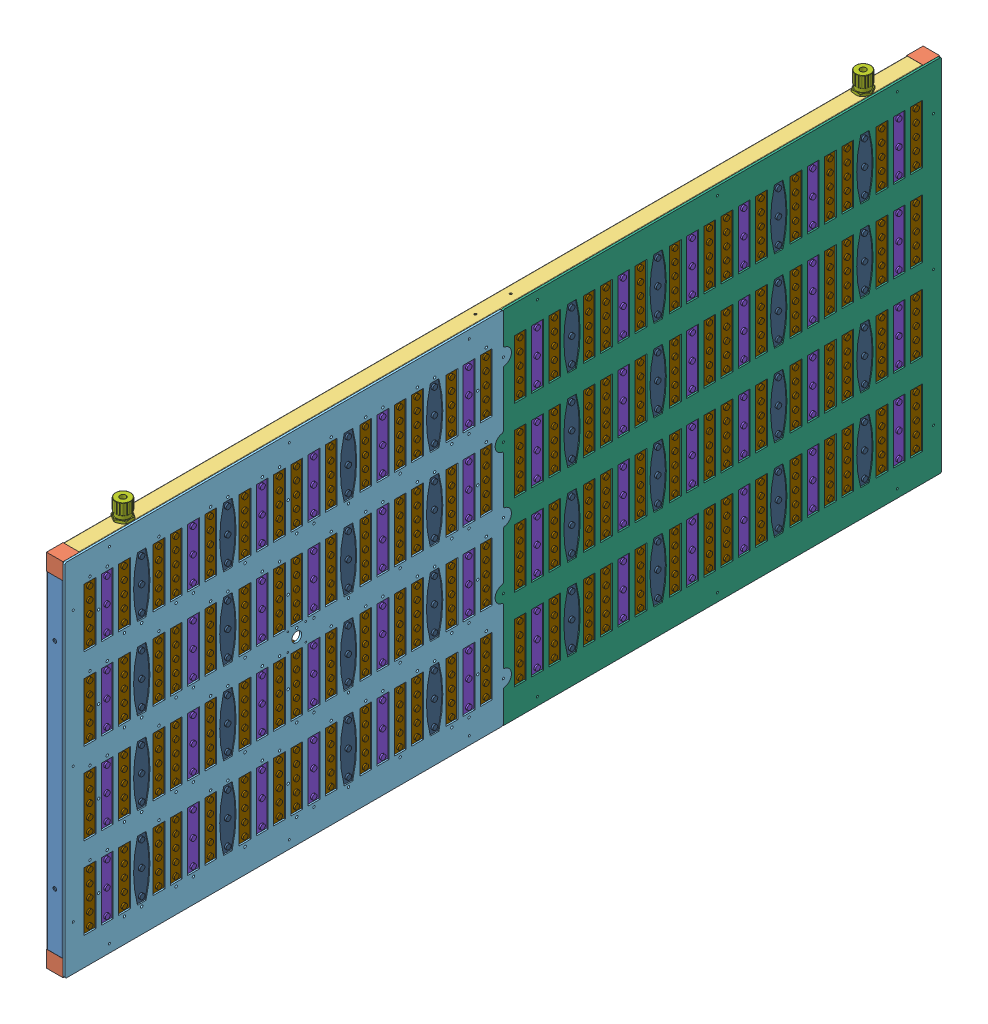
SolidWorks assembly 1_light_panel_assembly, configuration Default. Lengths in mm.
Overall size (35.45 587.2 1361.03).
207 component instances, 12 part files, 56 mates.
Components (placement in the parent):
- 1_bar_01-1: 1_bar_01 [Default] at (165.4428 -22.2621 425.3601) size (25.4 508 25.4)
- 1_corner-1: 1_corner [Default] at (165.4428 457.6709 425.3601) x (-1 0 0) z (0 0 -1) size (25.7 53.77 53.77)
- 1_bar_02-1: 1_bar_02 [Default] at (165.4428 498.5903 -897.1163) x (1 0 0) z (0 -1 0) size (25.4 1309.62 25.4)
- 1_bar_02-2: 1_bar_02 [Default] at (165.4428 -35.1145 -897.1163) x (1 0 0) z (0 -1 0) size (25.4 1309.62 25.4)
- 1_corner-2: 1_corner [Default] at (165.4428 -35.1145 384.4407) x (-1 0 0) z (0 1 0) size (25.7 53.77 53.77)
- 1_corner-3: 1_corner [Default] at (165.4428 498.5903 -869.0493) x (-1 0 0) z (0 -1 0) size (25.7 53.77 53.77)
- 1_corner-4: 1_corner [Default] at (165.4428 5.8049 -909.9687) x (-1 0 0) z (0 0 1) size (25.7 53.77 53.77)
- 1_bar_01-2: 1_bar_01 [Default] at (165.4428 -22.2621 -909.9687) size (25.4 508 25.4)
- 1_bar_03-1: 1_bar_03 [Default] at (165.4428 -22.1097 -242.4567) size (25.4 508 25.4)
- 1_panel_bottom_left-1: 1_panel_bottom_left [Default] at (178.1428 231.7379 97.8779) x (0 0 -1) z (0 -1 0) size (693.14 3.17 559.1)
- 1_panel_bottom_right-1: 1_panel_bottom_right [Default] at (178.1428 231.7379 -582.4865) x (0 0 1) z (0 1 0) size (693.06 3.17 559.1)
- 7529K104_STRAIGHT CORD GRIP-1: 7529K104_STRAIGHT CORD GRIP [7529K104] at (165.4428 500.3683 332.2437) x (-0.5 0 -0.866025) z (0 1 0) size (23.66 27.28 39.41)
- 7529K104_STRAIGHT CORD GRIP-2: 7529K104_STRAIGHT CORD GRIP [7529K104] at (165.4428 500.3683 -816.8523) x (0 0 -1) z (0 1 0) size (23.66 27.28 39.41)
- 1_top_panel-1: 1_top_panel [Default] at (152.7428 231.7379 -242.3043) x (0 1 0) z (0 0 1) size (559.1 0.79 1360.73) (hidden)
- 1_ear-1: 1_ear [Default] at (178.1428 231.7379 -923.4624) x (0 1 0) z (1 0 0) size (444.5 3.33 530.52) (hidden)
- ge_light_blue-1: ge_light_blue [Default] at (173.8248 494.1029 346.6803) x (0 1 0) z (0 0 -1) size (99.54 9.65 18.11)
- ge_light_red-1: ge_light_red [Default] at (173.8248 494.1029 373.4309) x (0 1 0) z (0 0 -1) size (99.54 9.65 18.11)
- ge_light_white-1: ge_light_white [Default] at (173.0628 427.1769 298.7113) x (0 0 -1) z (1 0 0) size (25.4 109.73 10.92)
- ge_light_red-2: ge_light_red [Default] at (173.8248 494.1029 319.9363) x (0 1 0) z (0 0 -1) size (99.54 9.65 18.11)
- ge_light_red-3: ge_light_red [Default] at (173.8248 494.1029 266.4416) x (0 1 0) z (0 0 -1) size (99.54 9.65 18.11)
- ge_light_red-4: ge_light_red [Default] at (173.8248 494.1029 239.6943) x (0 1 0) z (0 0 -1) size (99.54 9.65 18.11)
- ge_light_red-5: ge_light_red [Default] at (173.8248 494.1029 186.1997) x (0 1 0) z (0 0 -1) size (99.54 9.65 18.11)
- ge_light_red-6: ge_light_red [Default] at (173.8248 494.1029 132.7051) x (0 1 0) z (0 0 -1) size (99.54 9.65 18.11)
- ge_light_red-7: ge_light_red [Default] at (173.8248 494.1029 79.2104) x (0 1 0) z (0 0 -1) size (99.54 9.65 18.11)
- ge_light_red-8: ge_light_red [Default] at (173.8248 494.1029 52.4631) x (0 1 0) z (0 0 -1) size (99.54 9.65 18.11)
- ge_light_red-9: ge_light_red [Default] at (173.8248 494.1029 -1.0315) x (0 1 0) z (0 0 -1) size (99.54 9.65 18.11)
- ge_light_red-10: ge_light_red [Default] at (173.8248 494.1029 -54.5261) x (0 1 0) z (0 0 -1) size (99.54 9.65 18.11)
- ge_light_red-11: ge_light_red [Default] at (173.8248 494.1029 -108.0207) x (0 1 0) z (0 0 -1) size (99.54 9.65 18.11)
- ge_light_red-12: ge_light_red [Default] at (173.8248 494.1029 -134.7681) x (0 1 0) z (0 0 -1) size (99.54 9.65 18.11)
- ge_light_red-13: ge_light_red [Default] at (173.8248 494.1029 -188.2627) x (0 1 0) z (0 0 -1) size (99.54 9.65 18.11)
- ge_light_red-14: ge_light_red [Default] at (173.8248 494.1029 -241.7573) x (0 1 0) z (0 0 -1) size (99.54 9.65 18.11)
- ge_light_blue-2: ge_light_blue [Default] at (173.8248 494.1029 212.9437) x (0 1 0) z (0 0 -1) size (99.54 9.65 18.11)
- ge_light_blue-3: ge_light_blue [Default] at (173.8248 494.1029 105.9545) x (0 1 0) z (0 0 -1) size (99.54 9.65 18.11)
- ge_light_blue-4: ge_light_blue [Default] at (173.8248 494.1029 25.7125) x (0 1 0) z (0 0 -1) size (99.54 9.65 18.11)
- ge_light_blue-5: ge_light_blue [Default] at (173.8248 494.1029 -81.2767) x (0 1 0) z (0 0 -1) size (99.54 9.65 18.11)
- ge_light_blue-6: ge_light_blue [Default] at (173.8248 494.1029 -215.0133) x (0 1 0) z (0 0 -1) size (99.54 9.65 18.11)
- ge_light_white-2: ge_light_white [Default] at (173.0628 427.1769 164.9748) x (0 0 -1) z (1 0 0) size (25.4 109.73 10.92)
- ge_light_white-3: ge_light_white [Default] at (173.0628 427.1769 -22.2564) x (0 0 -1) z (1 0 0) size (25.4 109.73 10.92)
- ge_light_white-4: ge_light_white [Default] at (173.0628 427.1769 -155.993) x (0 0 -1) z (1 0 0) size (25.4 109.73 10.92)
- ge_light_white-5: ge_light_white [Default] at (173.0628 300.1007 298.7113) x (0 0 -1) z (1 0 0) size (25.4 109.73 10.92)
- ge_light_white-6: ge_light_white [Default] at (173.0628 173.0245 298.7113) x (0 0 -1) z (1 0 0) size (25.4 109.73 10.92)
- ge_light_white-7: ge_light_white [Default] at (173.0628 45.9483 298.7113) x (0 0 -1) z (1 0 0) size (25.4 109.73 10.92)
- ge_light_white-8: ge_light_white [Default] at (173.0628 300.1007 164.9748) x (0 0 -1) z (1 0 0) size (25.4 109.73 10.92)
- ge_light_white-9: ge_light_white [Default] at (173.0628 173.0245 164.9748) x (0 0 -1) z (1 0 0) size (25.4 109.73 10.92)
- ge_light_white-10: ge_light_white [Default] at (173.0628 45.9483 164.9748) x (0 0 -1) z (1 0 0) size (25.4 109.73 10.92)
- ge_light_white-11: ge_light_white [Default] at (173.0628 300.1007 -22.2564) x (0 0 -1) z (1 0 0) size (25.4 109.73 10.92)
- ge_light_white-12: ge_light_white [Default] at (173.0628 173.0245 -22.2564) x (0 0 -1) z (1 0 0) size (25.4 109.73 10.92)
- ge_light_white-13: ge_light_white [Default] at (173.0628 45.9483 -22.2564) x (0 0 -1) z (1 0 0) size (25.4 109.73 10.92)
- ge_light_white-14: ge_light_white [Default] at (173.0628 300.1007 -155.993) x (0 0 -1) z (1 0 0) size (25.4 109.73 10.92)
- ge_light_white-15: ge_light_white [Default] at (173.0628 173.0245 -155.993) x (0 0 -1) z (1 0 0) size (25.4 109.73 10.92)
- ge_light_white-16: ge_light_white [Default] at (173.0628 45.9483 -155.993) x (0 0 -1) z (1 0 0) size (25.4 109.73 10.92)
- ge_light_blue-8: ge_light_blue [Default] at (173.8248 367.0267 346.6803) x (0 1 0) z (0 0 -1) size (99.54 9.65 18.11)
- ge_light_blue-9: ge_light_blue [Default] at (173.8248 239.9505 346.6803) x (0 1 0) z (0 0 -1) size (99.54 9.65 18.11)
- ge_light_blue-10: ge_light_blue [Default] at (173.8248 112.8743 346.6803) x (0 1 0) z (0 0 -1) size (99.54 9.65 18.11)
- ge_light_blue-11: ge_light_blue [Default] at (173.8248 367.0267 212.9437) x (0 1 0) z (0 0 -1) size (99.54 9.65 18.11)
- ge_light_blue-12: ge_light_blue [Default] at (173.8248 239.9505 212.9437) x (0 1 0) z (0 0 -1) size (99.54 9.65 18.11)
- ge_light_blue-13: ge_light_blue [Default] at (173.8248 112.8743 212.9437) x (0 1 0) z (0 0 -1) size (99.54 9.65 18.11)
- ge_light_blue-14: ge_light_blue [Default] at (173.8248 367.0267 105.9545) x (0 1 0) z (0 0 -1) size (99.54 9.65 18.11)
- ge_light_blue-15: ge_light_blue [Default] at (173.8248 239.9505 105.9545) x (0 1 0) z (0 0 -1) size (99.54 9.65 18.11)
- ge_light_blue-16: ge_light_blue [Default] at (173.8248 112.8743 105.9545) x (0 1 0) z (0 0 -1) size (99.54 9.65 18.11)
- ge_light_blue-17: ge_light_blue [Default] at (173.8248 367.0267 25.7125) x (0 1 0) z (0 0 -1) size (99.54 9.65 18.11)
- ge_light_blue-18: ge_light_blue [Default] at (173.8248 239.9505 25.7125) x (0 1 0) z (0 0 -1) size (99.54 9.65 18.11)
- ge_light_blue-19: ge_light_blue [Default] at (173.8248 112.8743 25.7125) x (0 1 0) z (0 0 -1) size (99.54 9.65 18.11)
- ge_light_blue-20: ge_light_blue [Default] at (173.8248 367.0267 -81.2767) x (0 1 0) z (0 0 -1) size (99.54 9.65 18.11)
- ge_light_blue-21: ge_light_blue [Default] at (173.8248 239.9505 -81.2767) x (0 1 0) z (0 0 -1) size (99.54 9.65 18.11)
- ge_light_blue-22: ge_light_blue [Default] at (173.8248 112.8743 -81.2767) x (0 1 0) z (0 0 -1) size (99.54 9.65 18.11)
- ge_light_blue-23: ge_light_blue [Default] at (173.8248 367.0267 -215.0133) x (0 1 0) z (0 0 -1) size (99.54 9.65 18.11)
- ge_light_blue-24: ge_light_blue [Default] at (173.8248 239.9505 -215.0133) x (0 1 0) z (0 0 -1) size (99.54 9.65 18.11)
- ge_light_blue-25: ge_light_blue [Default] at (173.8248 112.8743 -215.0133) x (0 1 0) z (0 0 -1) size (99.54 9.65 18.11)
- ge_light_red-15: ge_light_red [Default] at (173.8248 367.0267 373.4309) x (0 1 0) z (0 0 -1) size (99.54 9.65 18.11)
- ge_light_red-16: ge_light_red [Default] at (173.8248 239.9505 373.4309) x (0 1 0) z (0 0 -1) size (99.54 9.65 18.11)
- ge_light_red-17: ge_light_red [Default] at (173.8248 112.8743 373.4309) x (0 1 0) z (0 0 -1) size (99.54 9.65 18.11)
- ge_light_red-18: ge_light_red [Default] at (173.8248 367.0267 319.9363) x (0 1 0) z (0 0 -1) size (99.54 9.65 18.11)
- ge_light_red-19: ge_light_red [Default] at (173.8248 239.9505 319.9363) x (0 1 0) z (0 0 -1) size (99.54 9.65 18.11)
- ge_light_red-20: ge_light_red [Default] at (173.8248 112.8743 319.9363) x (0 1 0) z (0 0 -1) size (99.54 9.65 18.11)
- ge_light_red-21: ge_light_red [Default] at (173.8248 367.0267 266.4416) x (0 1 0) z (0 0 -1) size (99.54 9.65 18.11)
- ge_light_red-22: ge_light_red [Default] at (173.8248 239.9505 266.4416) x (0 1 0) z (0 0 -1) size (99.54 9.65 18.11)
- ge_light_red-23: ge_light_red [Default] at (173.8248 112.8743 266.4416) x (0 1 0) z (0 0 -1) size (99.54 9.65 18.11)
- ge_light_red-24: ge_light_red [Default] at (173.8248 367.0267 239.6943) x (0 1 0) z (0 0 -1) size (99.54 9.65 18.11)
- ge_light_red-25: ge_light_red [Default] at (173.8248 239.9505 239.6943) x (0 1 0) z (0 0 -1) size (99.54 9.65 18.11)
- ge_light_red-26: ge_light_red [Default] at (173.8248 112.8743 239.6943) x (0 1 0) z (0 0 -1) size (99.54 9.65 18.11)
- ge_light_red-27: ge_light_red [Default] at (173.8248 367.0267 186.1997) x (0 1 0) z (0 0 -1) size (99.54 9.65 18.11)
- ge_light_red-28: ge_light_red [Default] at (173.8248 239.9505 186.1997) x (0 1 0) z (0 0 -1) size (99.54 9.65 18.11)
- ge_light_red-29: ge_light_red [Default] at (173.8248 112.8743 186.1997) x (0 1 0) z (0 0 -1) size (99.54 9.65 18.11)
- ge_light_red-30: ge_light_red [Default] at (173.8248 367.0267 132.7051) x (0 1 0) z (0 0 -1) size (99.54 9.65 18.11)
- ge_light_red-31: ge_light_red [Default] at (173.8248 239.9505 132.7051) x (0 1 0) z (0 0 -1) size (99.54 9.65 18.11)
- ge_light_red-32: ge_light_red [Default] at (173.8248 112.8743 132.7051) x (0 1 0) z (0 0 -1) size (99.54 9.65 18.11)
- ge_light_red-33: ge_light_red [Default] at (173.8248 367.0267 79.2104) x (0 1 0) z (0 0 -1) size (99.54 9.65 18.11)
- ge_light_red-34: ge_light_red [Default] at (173.8248 239.9505 79.2104) x (0 1 0) z (0 0 -1) size (99.54 9.65 18.11)
- ge_light_red-35: ge_light_red [Default] at (173.8248 112.8743 79.2104) x (0 1 0) z (0 0 -1) size (99.54 9.65 18.11)
- ge_light_red-36: ge_light_red [Default] at (173.8248 367.0267 52.4631) x (0 1 0) z (0 0 -1) size (99.54 9.65 18.11)
- ge_light_red-37: ge_light_red [Default] at (173.8248 239.9505 52.4631) x (0 1 0) z (0 0 -1) size (99.54 9.65 18.11)
- ge_light_red-38: ge_light_red [Default] at (173.8248 112.8743 52.4631) x (0 1 0) z (0 0 -1) size (99.54 9.65 18.11)
- ge_light_red-39: ge_light_red [Default] at (173.8248 367.0267 -1.0315) x (0 1 0) z (0 0 -1) size (99.54 9.65 18.11)
- ge_light_red-40: ge_light_red [Default] at (173.8248 239.9505 -1.0315) x (0 1 0) z (0 0 -1) size (99.54 9.65 18.11)
- ge_light_red-41: ge_light_red [Default] at (173.8248 112.8743 -1.0315) x (0 1 0) z (0 0 -1) size (99.54 9.65 18.11)
- ge_light_red-42: ge_light_red [Default] at (173.8248 367.0267 -54.5261) x (0 1 0) z (0 0 -1) size (99.54 9.65 18.11)
- ge_light_red-43: ge_light_red [Default] at (173.8248 239.9505 -54.5261) x (0 1 0) z (0 0 -1) size (99.54 9.65 18.11)
- ge_light_red-44: ge_light_red [Default] at (173.8248 112.8743 -54.5261) x (0 1 0) z (0 0 -1) size (99.54 9.65 18.11)
- ge_light_red-45: ge_light_red [Default] at (173.8248 367.0267 -108.0207) x (0 1 0) z (0 0 -1) size (99.54 9.65 18.11)
- ge_light_red-46: ge_light_red [Default] at (173.8248 239.9505 -108.0207) x (0 1 0) z (0 0 -1) size (99.54 9.65 18.11)
- ge_light_red-47: ge_light_red [Default] at (173.8248 112.8743 -108.0207) x (0 1 0) z (0 0 -1) size (99.54 9.65 18.11)
- ge_light_red-48: ge_light_red [Default] at (173.8248 367.0267 -134.7681) x (0 1 0) z (0 0 -1) size (99.54 9.65 18.11)
- ge_light_red-49: ge_light_red [Default] at (173.8248 239.9505 -134.7681) x (0 1 0) z (0 0 -1) size (99.54 9.65 18.11)
- ge_light_red-50: ge_light_red [Default] at (173.8248 112.8743 -134.7681) x (0 1 0) z (0 0 -1) size (99.54 9.65 18.11)
- ge_light_red-51: ge_light_red [Default] at (173.8248 367.0267 -188.2627) x (0 1 0) z (0 0 -1) size (99.54 9.65 18.11)
- ge_light_red-52: ge_light_red [Default] at (173.8248 239.9505 -188.2627) x (0 1 0) z (0 0 -1) size (99.54 9.65 18.11)
- ge_light_red-53: ge_light_red [Default] at (173.8248 112.8743 -188.2627) x (0 1 0) z (0 0 -1) size (99.54 9.65 18.11)
- ge_light_red-54: ge_light_red [Default] at (173.8248 367.0267 -241.7573) x (0 1 0) z (0 0 -1) size (99.54 9.65 18.11)
- ge_light_red-55: ge_light_red [Default] at (173.8248 239.9505 -241.7573) x (0 1 0) z (0 0 -1) size (99.54 9.65 18.11)
- ge_light_red-56: ge_light_red [Default] at (173.8248 112.8743 -241.7573) x (0 1 0) z (0 0 -1) size (99.54 9.65 18.11)
- ge_light_white-17: ge_light_white [Default] at (173.0628 427.1769 -369.1055) x (0 0 -1) z (1 0 0) size (25.4 109.73 10.92)
- ge_light_blue-26: ge_light_blue [Default] at (173.8248 494.1029 -321.1365) x (0 1 0) z (0 0 -1) size (99.54 9.65 18.11)
- ge_light_red-57: ge_light_red [Default] at (173.8248 494.1029 -294.3859) x (0 1 0) z (0 0 -1) size (99.54 9.65 18.11)
- ge_light_white-18: ge_light_white [Default] at (173.0628 427.1769 -502.842) x (0 0 -1) z (1 0 0) size (25.4 109.73 10.92)
- ge_light_white-19: ge_light_white [Default] at (173.0628 427.1769 -690.0732) x (0 0 -1) z (1 0 0) size (25.4 109.73 10.92)
- ge_light_white-20: ge_light_white [Default] at (173.0628 427.1769 -823.8098) x (0 0 -1) z (1 0 0) size (25.4 109.73 10.92)
- ge_light_blue-27: ge_light_blue [Default] at (173.8248 494.1029 -454.8731) x (0 1 0) z (0 0 -1) size (99.54 9.65 18.11)
- ge_light_blue-28: ge_light_blue [Default] at (173.8248 494.1029 -561.8623) x (0 1 0) z (0 0 -1) size (99.54 9.65 18.11)
- ge_light_blue-29: ge_light_blue [Default] at (173.8248 494.1029 -642.1043) x (0 1 0) z (0 0 -1) size (99.54 9.65 18.11)
- ge_light_blue-30: ge_light_blue [Default] at (173.8248 494.1029 -749.0935) x (0 1 0) z (0 0 -1) size (99.54 9.65 18.11)
- ge_light_blue-31: ge_light_blue [Default] at (173.8248 494.1029 -882.8301) x (0 1 0) z (0 0 -1) size (99.54 9.65 18.11)
- ge_light_white-21: ge_light_white [Default] at (173.0628 300.1007 -369.1055) x (0 0 -1) z (1 0 0) size (25.4 109.73 10.92)
- ge_light_white-22: ge_light_white [Default] at (173.0628 173.0245 -369.1055) x (0 0 -1) z (1 0 0) size (25.4 109.73 10.92)
- ge_light_white-23: ge_light_white [Default] at (173.0628 45.9483 -369.1055) x (0 0 -1) z (1 0 0) size (25.4 109.73 10.92)
- ge_light_white-24: ge_light_white [Default] at (173.0628 300.1007 -502.842) x (0 0 -1) z (1 0 0) size (25.4 109.73 10.92)
- ge_light_white-25: ge_light_white [Default] at (173.0628 173.0245 -502.842) x (0 0 -1) z (1 0 0) size (25.4 109.73 10.92)
- ge_light_white-26: ge_light_white [Default] at (173.0628 45.9483 -502.842) x (0 0 -1) z (1 0 0) size (25.4 109.73 10.92)
- ge_light_white-27: ge_light_white [Default] at (173.0628 300.1007 -690.0732) x (0 0 -1) z (1 0 0) size (25.4 109.73 10.92)
- ge_light_white-28: ge_light_white [Default] at (173.0628 173.0245 -690.0732) x (0 0 -1) z (1 0 0) size (25.4 109.73 10.92)
- ge_light_white-29: ge_light_white [Default] at (173.0628 45.9483 -690.0732) x (0 0 -1) z (1 0 0) size (25.4 109.73 10.92)
- ge_light_white-30: ge_light_white [Default] at (173.0628 300.1007 -823.8098) x (0 0 -1) z (1 0 0) size (25.4 109.73 10.92)
- ge_light_white-31: ge_light_white [Default] at (173.0628 173.0245 -823.8098) x (0 0 -1) z (1 0 0) size (25.4 109.73 10.92)
- ge_light_white-32: ge_light_white [Default] at (173.0628 45.9483 -823.8098) x (0 0 -1) z (1 0 0) size (25.4 109.73 10.92)
- ge_light_blue-32: ge_light_blue [Default] at (173.8248 367.0267 -321.1365) x (0 1 0) z (0 0 -1) size (99.54 9.65 18.11)
- ge_light_blue-33: ge_light_blue [Default] at (173.8248 239.9505 -321.1365) x (0 1 0) z (0 0 -1) size (99.54 9.65 18.11)
- ge_light_blue-34: ge_light_blue [Default] at (173.8248 112.8743 -321.1365) x (0 1 0) z (0 0 -1) size (99.54 9.65 18.11)
- ge_light_blue-35: ge_light_blue [Default] at (173.8248 367.0267 -454.8731) x (0 1 0) z (0 0 -1) size (99.54 9.65 18.11)
- ge_light_blue-36: ge_light_blue [Default] at (173.8248 239.9505 -454.8731) x (0 1 0) z (0 0 -1) size (99.54 9.65 18.11)
- ge_light_blue-37: ge_light_blue [Default] at (173.8248 112.8743 -454.8731) x (0 1 0) z (0 0 -1) size (99.54 9.65 18.11)
- ge_light_blue-38: ge_light_blue [Default] at (173.8248 367.0267 -561.8623) x (0 1 0) z (0 0 -1) size (99.54 9.65 18.11)
- ge_light_blue-39: ge_light_blue [Default] at (173.8248 239.9505 -561.8623) x (0 1 0) z (0 0 -1) size (99.54 9.65 18.11)
- ge_light_blue-40: ge_light_blue [Default] at (173.8248 112.8743 -561.8623) x (0 1 0) z (0 0 -1) size (99.54 9.65 18.11)
- ge_light_blue-41: ge_light_blue [Default] at (173.8248 367.0267 -642.1043) x (0 1 0) z (0 0 -1) size (99.54 9.65 18.11)
- ge_light_blue-42: ge_light_blue [Default] at (173.8248 239.9505 -642.1043) x (0 1 0) z (0 0 -1) size (99.54 9.65 18.11)
- ge_light_blue-43: ge_light_blue [Default] at (173.8248 112.8743 -642.1043) x (0 1 0) z (0 0 -1) size (99.54 9.65 18.11)
- ge_light_blue-44: ge_light_blue [Default] at (173.8248 367.0267 -749.0935) x (0 1 0) z (0 0 -1) size (99.54 9.65 18.11)
- ge_light_blue-45: ge_light_blue [Default] at (173.8248 239.9505 -749.0935) x (0 1 0) z (0 0 -1) size (99.54 9.65 18.11)
- ge_light_blue-46: ge_light_blue [Default] at (173.8248 112.8743 -749.0935) x (0 1 0) z (0 0 -1) size (99.54 9.65 18.11)
- ge_light_blue-47: ge_light_blue [Default] at (173.8248 367.0267 -882.8301) x (0 1 0) z (0 0 -1) size (99.54 9.65 18.11)
- ge_light_blue-48: ge_light_blue [Default] at (173.8248 239.9505 -882.8301) x (0 1 0) z (0 0 -1) size (99.54 9.65 18.11)
- ge_light_blue-49: ge_light_blue [Default] at (173.8248 112.8743 -882.8301) x (0 1 0) z (0 0 -1) size (99.54 9.65 18.11)
- ge_light_red-58: ge_light_red [Default] at (173.8248 367.0267 -294.3859) x (0 1 0) z (0 0 -1) size (99.54 9.65 18.11)
- ge_light_red-59: ge_light_red [Default] at (173.8248 239.9505 -294.3859) x (0 1 0) z (0 0 -1) size (99.54 9.65 18.11)
- ge_light_red-60: ge_light_red [Default] at (173.8248 112.8743 -294.3859) x (0 1 0) z (0 0 -1) size (99.54 9.65 18.11)
- ge_light_red-61: ge_light_red [Default] at (173.8248 367.0267 -347.8805) x (0 1 0) z (0 0 -1) size (99.54 9.65 18.11)
- ge_light_red-62: ge_light_red [Default] at (173.8248 239.9505 -347.8805) x (0 1 0) z (0 0 -1) size (99.54 9.65 18.11)
- ge_light_red-63: ge_light_red [Default] at (173.8248 112.8743 -347.8805) x (0 1 0) z (0 0 -1) size (99.54 9.65 18.11)
- ge_light_red-64: ge_light_red [Default] at (173.8248 367.0267 -401.3752) x (0 1 0) z (0 0 -1) size (99.54 9.65 18.11)
- ge_light_red-65: ge_light_red [Default] at (173.8248 239.9505 -401.3752) x (0 1 0) z (0 0 -1) size (99.54 9.65 18.11)
- ge_light_red-66: ge_light_red [Default] at (173.8248 112.8743 -401.3752) x (0 1 0) z (0 0 -1) size (99.54 9.65 18.11)
- ge_light_red-67: ge_light_red [Default] at (173.8248 367.0267 -428.1225) x (0 1 0) z (0 0 -1) size (99.54 9.65 18.11)
- ge_light_red-68: ge_light_red [Default] at (173.8248 239.9505 -428.1225) x (0 1 0) z (0 0 -1) size (99.54 9.65 18.11)
- ge_light_red-69: ge_light_red [Default] at (173.8248 112.8743 -428.1225) x (0 1 0) z (0 0 -1) size (99.54 9.65 18.11)
- ge_light_red-70: ge_light_red [Default] at (173.8248 367.0267 -481.6171) x (0 1 0) z (0 0 -1) size (99.54 9.65 18.11)
- ge_light_red-71: ge_light_red [Default] at (173.8248 239.9505 -481.6171) x (0 1 0) z (0 0 -1) size (99.54 9.65 18.11)
- ge_light_red-72: ge_light_red [Default] at (173.8248 112.8743 -481.6171) x (0 1 0) z (0 0 -1) size (99.54 9.65 18.11)
- ge_light_red-73: ge_light_red [Default] at (173.8248 367.0267 -535.1117) x (0 1 0) z (0 0 -1) size (99.54 9.65 18.11)
- ge_light_red-74: ge_light_red [Default] at (173.8248 239.9505 -535.1117) x (0 1 0) z (0 0 -1) size (99.54 9.65 18.11)
- ge_light_red-75: ge_light_red [Default] at (173.8248 112.8743 -535.1117) x (0 1 0) z (0 0 -1) size (99.54 9.65 18.11)
- ge_light_red-76: ge_light_red [Default] at (173.8248 367.0267 -588.6064) x (0 1 0) z (0 0 -1) size (99.54 9.65 18.11)
- ge_light_red-77: ge_light_red [Default] at (173.8248 239.9505 -588.6064) x (0 1 0) z (0 0 -1) size (99.54 9.65 18.11)
- ge_light_red-78: ge_light_red [Default] at (173.8248 112.8743 -588.6064) x (0 1 0) z (0 0 -1) size (99.54 9.65 18.11)
- ge_light_red-79: ge_light_red [Default] at (173.8248 367.0267 -615.3537) x (0 1 0) z (0 0 -1) size (99.54 9.65 18.11)
- ge_light_red-80: ge_light_red [Default] at (173.8248 239.9505 -615.3537) x (0 1 0) z (0 0 -1) size (99.54 9.65 18.11)
- ge_light_red-81: ge_light_red [Default] at (173.8248 112.8743 -615.3537) x (0 1 0) z (0 0 -1) size (99.54 9.65 18.11)
- ge_light_red-82: ge_light_red [Default] at (173.8248 367.0267 -668.8483) x (0 1 0) z (0 0 -1) size (99.54 9.65 18.11)
- ge_light_red-83: ge_light_red [Default] at (173.8248 239.9505 -668.8483) x (0 1 0) z (0 0 -1) size (99.54 9.65 18.11)
- ge_light_red-84: ge_light_red [Default] at (173.8248 112.8743 -668.8483) x (0 1 0) z (0 0 -1) size (99.54 9.65 18.11)
- ge_light_red-85: ge_light_red [Default] at (173.8248 367.0267 -722.3429) x (0 1 0) z (0 0 -1) size (99.54 9.65 18.11)
- ge_light_red-86: ge_light_red [Default] at (173.8248 239.9505 -722.3429) x (0 1 0) z (0 0 -1) size (99.54 9.65 18.11)
- ge_light_red-87: ge_light_red [Default] at (173.8248 112.8743 -722.3429) x (0 1 0) z (0 0 -1) size (99.54 9.65 18.11)
- ge_light_red-88: ge_light_red [Default] at (173.8248 367.0267 -775.8375) x (0 1 0) z (0 0 -1) size (99.54 9.65 18.11)
- ge_light_red-89: ge_light_red [Default] at (173.8248 239.9505 -775.8375) x (0 1 0) z (0 0 -1) size (99.54 9.65 18.11)
- ge_light_red-90: ge_light_red [Default] at (173.8248 112.8743 -775.8375) x (0 1 0) z (0 0 -1) size (99.54 9.65 18.11)
- ge_light_red-91: ge_light_red [Default] at (173.8248 367.0267 -802.5849) x (0 1 0) z (0 0 -1) size (99.54 9.65 18.11)
- ge_light_red-92: ge_light_red [Default] at (173.8248 239.9505 -802.5849) x (0 1 0) z (0 0 -1) size (99.54 9.65 18.11)
- ge_light_red-93: ge_light_red [Default] at (173.8248 112.8743 -802.5849) x (0 1 0) z (0 0 -1) size (99.54 9.65 18.11)
- ge_light_red-94: ge_light_red [Default] at (173.8248 367.0267 -856.0795) x (0 1 0) z (0 0 -1) size (99.54 9.65 18.11)
- ge_light_red-95: ge_light_red [Default] at (173.8248 239.9505 -856.0795) x (0 1 0) z (0 0 -1) size (99.54 9.65 18.11)
- ge_light_red-96: ge_light_red [Default] at (173.8248 112.8743 -856.0795) x (0 1 0) z (0 0 -1) size (99.54 9.65 18.11)
- ge_light_red-97: ge_light_red [Default] at (173.8248 367.0267 -909.5741) x (0 1 0) z (0 0 -1) size (99.54 9.65 18.11)
- ge_light_red-98: ge_light_red [Default] at (173.8248 239.9505 -909.5741) x (0 1 0) z (0 0 -1) size (99.54 9.65 18.11)
- ge_light_red-99: ge_light_red [Default] at (173.8248 112.8743 -909.5741) x (0 1 0) z (0 0 -1) size (99.54 9.65 18.11)
- ge_light_red-100: ge_light_red [Default] at (173.8248 494.1029 -347.8805) x (0 1 0) z (0 0 -1) size (99.54 9.65 18.11)
- ge_light_red-101: ge_light_red [Default] at (173.8248 494.1029 -401.3752) x (0 1 0) z (0 0 -1) size (99.54 9.65 18.11)
- ge_light_red-102: ge_light_red [Default] at (173.8248 494.1029 -428.1225) x (0 1 0) z (0 0 -1) size (99.54 9.65 18.11)
- ge_light_red-103: ge_light_red [Default] at (173.8248 494.1029 -481.6171) x (0 1 0) z (0 0 -1) size (99.54 9.65 18.11)
- ge_light_red-104: ge_light_red [Default] at (173.8248 494.1029 -535.1117) x (0 1 0) z (0 0 -1) size (99.54 9.65 18.11)
- ge_light_red-105: ge_light_red [Default] at (173.8248 494.1029 -588.6064) x (0 1 0) z (0 0 -1) size (99.54 9.65 18.11)
- ge_light_red-106: ge_light_red [Default] at (173.8248 494.1029 -615.3537) x (0 1 0) z (0 0 -1) size (99.54 9.65 18.11)
- ge_light_red-107: ge_light_red [Default] at (173.8248 494.1029 -668.8483) x (0 1 0) z (0 0 -1) size (99.54 9.65 18.11)
- ge_light_red-108: ge_light_red [Default] at (173.8248 494.1029 -722.3429) x (0 1 0) z (0 0 -1) size (99.54 9.65 18.11)
- ge_light_red-109: ge_light_red [Default] at (173.8248 494.1029 -775.8375) x (0 1 0) z (0 0 -1) size (99.54 9.65 18.11)
- ge_light_red-110: ge_light_red [Default] at (173.8248 494.1029 -802.5849) x (0 1 0) z (0 0 -1) size (99.54 9.65 18.11)
- ge_light_red-111: ge_light_red [Default] at (173.8248 494.1029 -856.0795) x (0 1 0) z (0 0 -1) size (99.54 9.65 18.11)
- ge_light_red-112: ge_light_red [Default] at (173.8248 494.1029 -909.5741) x (0 1 0) z (0 0 -1) size (99.54 9.65 18.11)
Mates (geometry in assembly coordinates):
- Coincident1: coincident anti-aligned: plane of 1_bar_01-1 through (154.3938 485.7379 436.4091) normal (1 0 0); plane of 1_corner-1 through (154.3938 485.7379 436.4091) normal (-1 0 0)
- Coincident2: coincident anti-aligned: plane of 1_bar_01-1 through (165.4428 485.7379 425.3601) normal (0 1 0); plane of 1_corner-1 through (165.4428 485.7379 425.3601) normal (0 -1 0)
- Coincident3: coincident anti-aligned: plane of 1_bar_01-1 through (154.3938 485.7379 436.4091) normal (0 0 -1); plane of 1_corner-1 through (176.4918 485.7379 436.4091) normal (0 0 1)
- Coincident4: coincident anti-aligned: plane of 1_corner-1 through (178.2952 511.4427 412.5077) normal (0 0 -1); plane of 1_bar_02-1 through (165.4428 498.5903 412.5077) normal (0 0 1)
- Coincident5: coincident anti-aligned: plane of 1_corner-1 through (176.4918 509.6393 384.4407) normal (0 1 0); plane of 1_bar_02-1 through (154.3938 509.6393 412.5077) normal (0 -1 0)
- Coincident6: coincident anti-aligned: plane of 1_corner-1 through (176.4918 487.5413 384.4407) normal (1 0 0); plane of 1_bar_02-1 through (176.4918 487.5413 412.5077) normal (-1 0 0)
- Coincident7: coincident aligned: plane of 1_bar_02-1 through (178.1428 485.8903 412.5077) normal (1 0 0); plane of 1_bar_02-2 through (178.1428 -47.8145 412.5077) normal (1 0 0)
- Coincident8: coincident anti-aligned: plane of 1_bar_01-1 through (176.4918 485.7379 436.4091) normal (-1 0 0); plane of 1_corner-2 through (176.4918 5.8049 414.3111) normal (1 0 0)
- Coincident9: coincident anti-aligned: plane of 1_bar_01-1 through (165.4428 -22.2621 425.3601) normal (0 -1 0); plane of 1_corner-2 through (178.2952 -22.2621 438.2125) normal (0 1 0)
- Coincident10: coincident anti-aligned: plane of 1_bar_01-1 through (154.3938 485.7379 414.3111) normal (0 0 1); plane of 1_corner-2 through (176.4918 5.8049 414.3111) normal (0 0 -1)
- Coincident11: coincident anti-aligned: plane of 1_bar_02-2 through (165.4428 -35.1145 412.5077) normal (0 0 1); plane of 1_corner-2 through (165.4428 -35.1145 412.5077) normal (0 0 -1)
- Coincident13: coincident anti-aligned: plane of 1_bar_02-2 through (154.3938 -46.1635 412.5077) normal (0 1 0); plane of 1_corner-2 through (176.4918 -46.1635 412.5077) normal (0 -1 0)
- Coincident15: coincident aligned: plane of 1_corner-2 through (178.2952 -22.2621 438.2125) normal (1 0 0); plane of 1_corner-3 through (178.2952 485.7379 -922.8211) normal (1 0 0)
- Coincident16: coincident anti-aligned: plane of 1_bar_02-1 through (165.4428 498.5903 -897.1163) normal (0 0 -1); plane of 1_corner-3 through (165.4428 498.5903 -897.1163) normal (0 0 1)
- Coincident17: coincident anti-aligned: plane of 1_bar_02-1 through (154.3938 509.6393 412.5077) normal (0 -1 0); plane of 1_corner-3 through (176.4918 509.6393 -897.1163) normal (0 1 0)
- Coincident18: coincident aligned: plane of 1_corner-3 through (178.2952 485.7379 -922.8211) normal (1 0 0); plane of 1_corner-4 through (178.2952 -47.9669 -897.1163) normal (1 0 0)
- Coincident19: coincident anti-aligned: plane of 1_bar_02-2 through (154.3938 -46.1635 412.5077) normal (0 1 0); plane of 1_corner-4 through (176.4918 -46.1635 -869.0493) normal (0 -1 0)
- Coincident20: coincident anti-aligned: plane of 1_bar_02-2 through (165.4428 -35.1145 -897.1163) normal (0 0 -1); plane of 1_corner-4 through (178.2952 -47.9669 -897.1163) normal (0 0 1)
- Coincident21: coincident aligned: plane of 1_bar_02-1 through (178.1428 485.8903 412.5077) normal (1 0 0); plane of 1_bar_01-2 through (178.1428 485.7379 -897.2687) normal (1 0 0)
- Coincident22: coincident anti-aligned: plane of 1_corner-3 through (176.4918 457.6709 -921.0177) normal (0 0 -1); plane of 1_bar_01-2 through (154.3938 485.7379 -921.0177) normal (0 0 1)
- Coincident23: coincident anti-aligned: plane of 1_corner-3 through (178.2952 485.7379 -922.8211) normal (0 -1 0); plane of 1_bar_01-2 through (165.4428 485.7379 -909.9687) normal (0 1 0)
- Coincident24: coincident aligned: plane of 1_bar_02-1 through (178.1428 485.8903 412.5077) normal (1 0 0); plane of 1_bar_03-1 through (178.1428 485.8903 -229.7567) normal (1 0 0)
- Coincident25: coincident anti-aligned: plane of 1_bar_02-1 through (152.7428 485.8903 412.5077) normal (0 -1 0); plane of 1_bar_03-1 through (165.4428 485.8903 -242.4567) normal (0 1 0)
- Distance1: distance = 642.112 mm anti-aligned: plane of 1_bar_03-1 through (152.7428 485.8903 -255.1567) normal (0 0 -1); plane of 1_bar_01-2 through (152.7428 485.7379 -897.2687) normal (0 0 1)
- Coincident31: coincident anti-aligned: plane of 1_bar_02-1 through (178.1428 485.8903 412.5077) normal (1 0 0); plane of 1_panel_bottom_left-1 through (178.1428 447.7903 -242.3043) normal (-1 0 0)
- Concentric6: concentric aligned: circle of 1_bar_02-1; cylinder of 7529K104_STRAIGHT CORD GRIP-1 through (165.4428 521.7678 332.2437) axis (0 -1 0) radius 10.414
- Coincident35: coincident anti-aligned: plane of 1_bar_02-1 through (152.7428 511.2903 412.5077) normal (0 1 0); plane of 7529K104_STRAIGHT CORD GRIP-1 through (153.6318 511.2903 339.0628) normal (0 -1 0)
- Parallel1: parallel aligned: plane of 1_panel_bottom_left-1 through (181.3178 447.7903 -242.3043) normal (1 0 0); plane of 7529K104_STRAIGHT CORD GRIP-1 through (177.2538 515.6591 339.0628) normal (1 0 0)
- Concentric7: concentric anti-aligned: circle of 1_bar_02-1; circle of 7529K104_STRAIGHT CORD GRIP-2
- Coincident37: coincident anti-aligned: plane of 1_bar_02-1 through (152.7428 511.2903 412.5077) normal (0 1 0); plane of 7529K104_STRAIGHT CORD GRIP-2 through (151.8047 511.2903 -816.8523) normal (0 -1 0)
- Coincident38: coincident anti-aligned: plane of 1_bar_02-1 through (152.7428 485.8903 412.5077) normal (-1 0 0); plane of 1_top_panel-1 through (152.7428 231.7379 -242.3043) normal (1 0 0)
- Coincident39: coincident aligned: plane of 1_bar_02-2 through (152.7428 -47.8145 412.5077) normal (0 -1 0); plane of 1_top_panel-1 through (151.9491 -47.8145 438.0601) normal (0 -1 0)
- Coincident40: coincident aligned: plane of 1_bar_01-1 through (152.7428 485.7379 438.0601) normal (0 0 1); plane of 1_top_panel-1 through (151.9491 -47.8145 438.0601) normal (0 0 1)
- Concentric10: concentric anti-aligned: circle of 1_bar_01-2; circle of 1_ear-1
- Concentric11: concentric anti-aligned: circle of 1_bar_01-2; circle of 1_ear-1
- Coincident48: coincident anti-aligned: plane of 1_bar_01-2 through (152.7428 485.7379 -922.6687) normal (0 0 -1); plane of 1_ear-1 through (178.1428 231.7379 -922.6687) normal (0 0 1)
- Coincident49: coincident aligned: plane of 1_bar_01-1 through (152.7428 485.7379 438.0601) normal (0 0 1); plane of 1_panel_bottom_left-1 through (181.3178 -47.8145 438.0601) normal (0 0 1)
- Coincident50: coincident aligned: plane of 1_bar_01-2 through (152.7428 485.7379 -922.6687) normal (0 0 -1); plane of 1_panel_bottom_right-1 through (181.3178 511.2903 -922.6687) normal (0 0 -1)
- Coincident51: coincident anti-aligned: plane of 1_bar_01-2 through (178.1428 485.7379 -897.2687) normal (1 0 0); plane of 1_panel_bottom_right-1 through (178.1428 15.6855 -242.3043) normal (-1 0 0)
- Coincident52: coincident aligned: plane of 1_bar_02-2 through (152.7428 -47.8145 412.5077) normal (0 -1 0); plane of 1_panel_bottom_right-1 through (181.3178 -47.8145 -922.6687) normal (0 -1 0)
- Coincident53: coincident aligned: plane of 1_bar_02-2 through (152.7428 -47.8145 412.5077) normal (0 -1 0); plane of 1_panel_bottom_left-1 through (181.3178 -47.8145 438.0601) normal (0 -1 0)
- Concentric12: concentric aligned: circle of 1_panel_bottom_right-1; circle of ?
- Concentric13: concentric aligned: circle of 1_panel_bottom_right-1; circle of ?
- Concentric14: concentric aligned: circle of 1_panel_bottom_right-1; circle of ?
- Coincident54: coincident anti-aligned: plane of 1_panel_bottom_right-1 through (178.1428 15.6855 -242.3043) normal (-1 0 0); plane of ? through (178.1428 217.7298 -548.9204) normal (1 0 0)
- Coincident58: coincident anti-aligned: plane of 1_panel_bottom_left-1 through (178.1428 447.7903 -242.3043) normal (-1 0 0); plane of ge_light_blue-1 through (178.1428 494.1029 346.6803) normal (1 0 0)
- Concentric15: concentric aligned: circle of 1_panel_bottom_left-1; circle of ge_light_blue-1
- Parallel2: parallel anti-aligned: plane of 1_panel_bottom_left-1 through (178.1428 376.9243 381.6456) normal (0 1 0); plane of ge_light_blue-1 through (179.9208 377.9403 381.6296) normal (0 -1 0)
- Coincident60: coincident anti-aligned: plane of 1_panel_bottom_left-1 through (178.1428 447.7903 -242.3043) normal (-1 0 0); plane of ge_light_red-1 through (178.1428 494.1029 373.4309) normal (1 0 0)
- Concentric16: concentric aligned: circle of 1_panel_bottom_left-1; circle of ge_light_red-1
- Parallel3: parallel anti-aligned: plane of 1_panel_bottom_left-1 through (178.1428 376.9243 408.3929) normal (0 1 0); plane of ge_light_red-1 through (179.9208 377.9403 408.3803) normal (0 -1 0)
- Concentric17: concentric aligned: circle of 1_panel_bottom_left-1; circle of ge_light_white-1
- Coincident62: coincident anti-aligned: plane of 1_panel_bottom_left-1 through (178.1428 447.7903 -242.3043) normal (-1 0 0); plane of ge_light_white-1 through (178.1428 476.7463 312.4693) normal (1 0 0)
- Parallel4: parallel aligned: plane of 1_panel_bottom_left-1 through (178.1428 376.9243 354.8983) normal (0 1 0); plane of ge_light_white-1 through (171.5388 464.0463 312.7233) normal (0 1 0)
- Parallel5: parallel aligned: plane of 1_bar_01-2 through (152.7428 485.7379 -922.6687) normal (0 0 -1); plane of 7529K104_STRAIGHT CORD GRIP-2 through (172.2619 515.6591 -828.6633) normal (0 0 -1)
- Concentric18: concentric aligned: circle of 1_panel_bottom_right-1; circle of ?
